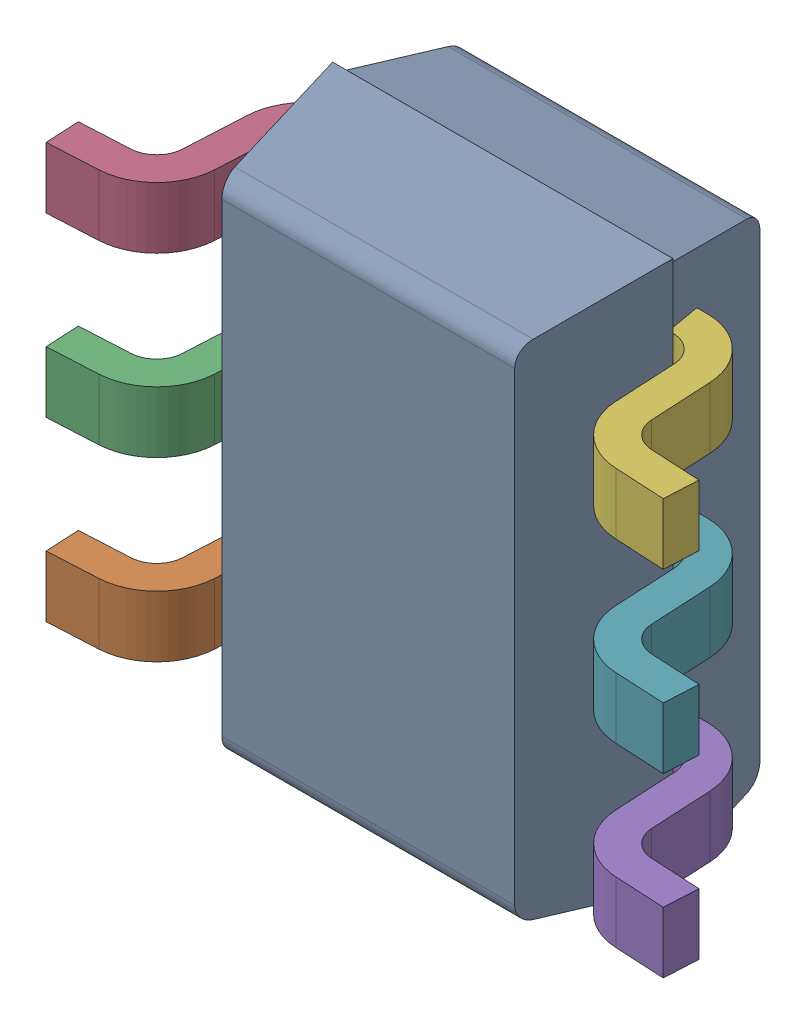
SolidWorks assembly U306_2PCB, configuration Default. Lengths in mm.
Overall size (2.28 2 0.95).
9 component instances, 7 part files, 0 mates.
Components (placement in the parent):
- DCK0006AakaMAA06-1: DCK0006AakaMAA06 [Default] at (136.4999 88.3001 -2.1938) x (0 -1 0) z (-1 0 0) size (2 0.95 2.28)
  - BODY_MAA06-1: BODY_MAA06 [Default] at origin size (2 0.9 1.25)
  - LEADS_MAA06-1: LEADS_MAA06 [Default] at (0.65 0 0) x (0 0 1) z (1 0 0) size (2.28 0.67 1.53)
    - LEADS_MAA06_3-1: LEADS_MAA06_3 [Default] at origin size (0.55 0.67 0.23)
    - LEADS_MAA06_4-1: LEADS_MAA06_4 [Default] at origin size (0.55 0.67 0.23)
    - LEADS_MAA06_5-1: LEADS_MAA06_5 [Default] at origin size (0.55 0.67 0.23)
    - LEADS_MAA06_6-1: LEADS_MAA06_6 [Default] at origin size (0.55 0.67 0.23)
    - LEADS_MAA06_7-1: LEADS_MAA06_7 [Default] at origin size (0.55 0.67 0.23)
    - LEADS_MAA06_8-1: LEADS_MAA06_8 [Default] at origin size (0.55 0.67 0.23)
